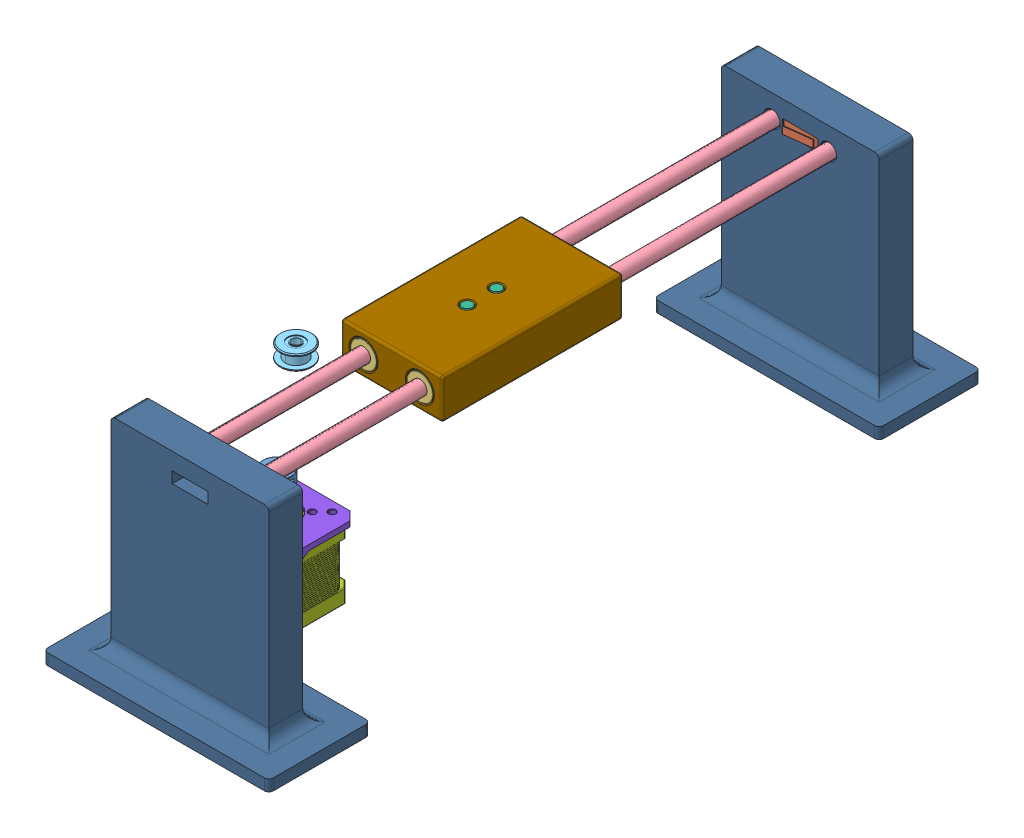
SolidWorks assembly TrackerPlatform, configuration Default. Lengths in mm.
Overall size (127 141.21 400.8).
21 component instances, 11 part files, 37 mates.
Components (placement in the parent):
- Teeth GT2 Pulley^TrackerPlatform-1: Teeth GT2 Pulley^TrackerPlatform [Varsayılan] at (44.45 -33.8487 -29.98) x (-0.053462 0 -0.99857) z (0 -1 0) size (16 16 14) (virtual)
- SPDT Lever Switch^TrackerPlatform-1: SPDT Lever Switch^TrackerPlatform [Default] at (44.417 -15.925 -329.85) x (-1 0 0) z (0 0 -1) size (20 6.4 16.53) (virtual)
- SPDT Lever Switch^TrackerPlatform-2: SPDT Lever Switch^TrackerPlatform [Default] at (44.417 -15.925 5.25) size (20 6.4 16.53) (virtual)
- LMU8 Linear Bearing^TrackerPlatform-1: LMU8 Linear Bearing^TrackerPlatform [Default] at (60.325 -12.7 -196.1468) size (15 15 24) (virtual)
- LMU8 Linear Bearing^TrackerPlatform-2: LMU8 Linear Bearing^TrackerPlatform [Default] at (28.575 -12.7 -172.1468) x (0.923728 0.383049 0) z (0 0 -1) size (15 15 24) (virtual)
- LMU8 Linear Bearing^TrackerPlatform-3: LMU8 Linear Bearing^TrackerPlatform [Default] at (60.325 -12.7 -118.5468) size (15 15 24) (virtual)
- LMU8 Linear Bearing^TrackerPlatform-4: LMU8 Linear Bearing^TrackerPlatform [Default] at (28.575 -12.7 -118.5468) size (15 15 24) (virtual)
- 350mm Linear Rail^TrackerPlatform-1: 350mm Linear Rail^TrackerPlatform [Default] at (60.325 -12.7 -337.3) x (0.609712 0.792623 0) z (0 0 1) size (8 8 350) (virtual)
- 350mm Linear Rail^TrackerPlatform-2: 350mm Linear Rail^TrackerPlatform [Default] at (28.575 -12.7 -337.3) x (0 -1 0) z (0 0 1) size (8 8 350) (virtual)
- Idler GT2-6 5mm.step^TrackerPlatform-2: Idler GT2-6 5mm.step^TrackerPlatform [Default] at (36.4446 16.3069 -48.6935) size (17.85 8.51 17.85) (virtual)
- 1-4x1.75 Dowel Pin^TrackerPlatform-1: 1-4x1.75 Dowel Pin^TrackerPlatform [Default] at (44.45 -46.0375 -153.6018) size (6.35 44.45 6.35) (virtual)
- 1-4x1.75 Dowel Pin^TrackerPlatform-2: 1-4x1.75 Dowel Pin^TrackerPlatform [Default] at (44.45 -46.0375 -137.0918) size (6.35 44.45 6.35) (virtual)
- Motor N17^TrackerPlatform-1: Motor N17^TrackerPlatform [Predeterminado] at (44.45 -92.0487 -29.98) x (0 0 -1) z (1 0 0) size (42.3 64.2 42.3) (virtual)
- NEMA 17 Motor Mount.step^TrackerPlatform-1: NEMA 17 Motor Mount.step^TrackerPlatform [Default] at (44.45 -2.0287 -3) x (0 -1 0) z (1 0 0) size (52.98 50.98 50) (virtual)
- Carriage^TrackerPlatform-1: Carriage^TrackerPlatform [Default] at (44.45 -23.8125 -145.3468) x (0 0 1) z (-1 0 0) size (101.6 22.23 57.15) (virtual)
- End Fixture^TrackerPlatform-1: End Fixture^TrackerPlatform [Default] at (44.45 -57.15 0) x (0 -1 0) z (-1 0 0) size (120.65 57.15 127) (virtual)
- End Fixture^TrackerPlatform-2: End Fixture^TrackerPlatform [Default] at (44.45 -57.15 -324.6) x (0 -1 0) z (1 0 0) size (120.65 57.15 127) (virtual)
- 2.5mmx5mm Standoff^TrackerPlatform-1: 2.5mmx5mm Standoff^TrackerPlatform [Default] at (-2.0742 -59.3398 -100.3321) size (4.9 4.9 5) (hidden, virtual)
- 2.5mmx5mm Standoff^TrackerPlatform-2: 2.5mmx5mm Standoff^TrackerPlatform [Default] at (-1.6992 -73.9326 -103.4686) size (4.9 4.9 5) (hidden, virtual)
- 2.5mmx5mm Standoff^TrackerPlatform-3: 2.5mmx5mm Standoff^TrackerPlatform [Default] at (-3.151 -75.2751 -95.8726) size (4.9 4.9 5) (hidden, virtual)
- 2.5mmx5mm Standoff^TrackerPlatform-4: 2.5mmx5mm Standoff^TrackerPlatform [Default] at (-9.8476 -68.7081 -99.2982) size (4.9 4.9 5) (hidden, virtual)
Mates (geometry in assembly coordinates):
- Concentric1: concentric: cylinder of LMU8 Linear Bearing^TrackerPlatform-3 through (60.325 -12.7 -94.5468) axis (0 0 -1) radius 7.5; cylinder of Carriage^TrackerPlatform-1 through (60.325 -12.7 -118.5468) axis (0 0 1) radius 7.55
- Coincident1: coincident: plane of LMU8 Linear Bearing^TrackerPlatform-3 through (60.325 -12.7 -94.5468) normal (0 0 1); plane of Carriage^TrackerPlatform-1 through (15.875 -1.5875 -94.5468) normal (0 0 1)
- Coincident2: coincident: plane of LMU8 Linear Bearing^TrackerPlatform-4 through (28.575 -12.7 -118.5468) normal (0 0 -1); plane of Carriage^TrackerPlatform-1 through (28.575 -12.7 -118.5468) normal (0 0 1)
- Concentric2: concentric: cylinder of LMU8 Linear Bearing^TrackerPlatform-4 through (28.575 -12.7 -94.5468) axis (0 0 -1) radius 7.5; cylinder of Carriage^TrackerPlatform-1 through (28.575 -12.7 -118.5468) axis (0 0 1) radius 7.55
- Coincident3: coincident: plane of LMU8 Linear Bearing^TrackerPlatform-1 through (60.325 -12.7 -172.1468) normal (0 0 1); plane of Carriage^TrackerPlatform-1 through (60.325 -12.7 -172.1468) normal (0 0 -1)
- Concentric3: concentric: cylinder of LMU8 Linear Bearing^TrackerPlatform-1 through (60.325 -12.7 -172.1468) axis (0 0 -1) radius 7.5; cylinder of Carriage^TrackerPlatform-1 through (60.325 -12.7 -172.1468) axis (0 0 -1) radius 7.55
- Coincident4: coincident: plane of LMU8 Linear Bearing^TrackerPlatform-2 through (28.575 -12.7 -172.1468) normal (0 0 1); plane of Carriage^TrackerPlatform-1 through (28.575 -12.7 -172.1468) normal (0 0 -1)
- Concentric4: concentric: cylinder of LMU8 Linear Bearing^TrackerPlatform-2 through (28.575 -12.7 -196.1468) axis (0 0 1) radius 7.5; cylinder of Carriage^TrackerPlatform-1 through (28.575 -12.7 -172.1468) axis (0 0 -1) radius 7.55
- Concentric5: concentric: cylinder of LMU8 Linear Bearing^TrackerPlatform-1 through (60.325 -12.7 -172.1468) axis (0 0 -1) radius 4; cylinder of 350mm Linear Rail^TrackerPlatform-1 through (60.325 -12.7 12.7) axis (0 0 -1) radius 4
- Concentric6: concentric: cylinder of LMU8 Linear Bearing^TrackerPlatform-2 through (28.575 -12.7 -196.1468) axis (0 0 1) radius 4; cylinder of 350mm Linear Rail^TrackerPlatform-2 through (28.575 -12.7 12.7) axis (0 0 -1) radius 4
- Coincident5: coincident: plane of 350mm Linear Rail^TrackerPlatform-1 through (60.325 -12.7 -337.3) normal (0 0 -1); plane of 350mm Linear Rail^TrackerPlatform-2 through (28.575 -12.7 -337.3) normal (0 0 -1)
- Concentric7: concentric: cylinder of 1-4x1.75 Dowel Pin^TrackerPlatform-1 through (44.45 -1.5875 -153.6018) axis (0 -1 0) radius 3.175; cylinder of Carriage^TrackerPlatform-1 through (44.45 -23.8125 -153.6018) axis (0 1 0) radius 3.175
- Coincident7: coincident: plane of 1-4x1.75 Dowel Pin^TrackerPlatform-1 through (44.45 -1.5875 -153.6018) normal (0 1 0); plane of Carriage^TrackerPlatform-1 through (44.45 -1.5875 -145.3468) normal (0 1 0)
- Concentric9: concentric: cylinder of 1-4x1.75 Dowel Pin^TrackerPlatform-2 through (44.45 -1.5875 -137.0918) axis (0 -1 0) radius 3.175; cylinder of Carriage^TrackerPlatform-1 through (44.45 -23.8125 -137.0918) axis (0 1 0) radius 3.175
- Coincident8: coincident: plane of 1-4x1.75 Dowel Pin^TrackerPlatform-2 through (44.45 -1.5875 -137.0918) normal (0 1 0); plane of Carriage^TrackerPlatform-1 through (44.45 -1.5875 -145.3468) normal (0 1 0)
- Coincident12: coincident: plane of End Fixture^TrackerPlatform-1 through (44.45 -57.15 0) normal (0 0 -1); plane of assembly through (0 0 0) normal (0 0 1)
- Coincident13: coincident: plane of End Fixture^TrackerPlatform-1 through (0 0 19.05) normal (0 1 0); plane of assembly through (0 0 0) normal (0 1 0)
- Coincident14: coincident: plane of End Fixture^TrackerPlatform-1 through (0 0 19.05) normal (-1 0 0); plane of assembly through (0 0 0) normal (1 0 0)
- Concentric10: concentric: cylinder of 350mm Linear Rail^TrackerPlatform-2 through (28.575 -12.7 12.7) axis (0 0 -1) radius 4; cylinder of End Fixture^TrackerPlatform-1 through (28.575 -12.7 12.7) axis (0 0 -1) radius 4
- Coincident15: coincident: plane of 350mm Linear Rail^TrackerPlatform-1 through (60.325 -12.7 12.7) normal (0 0 1); plane of End Fixture^TrackerPlatform-1 through (60.325 -12.7 12.7) normal (0 0 -1)
- Concentric11: concentric: cylinder of 350mm Linear Rail^TrackerPlatform-1 through (60.325 -12.7 12.7) axis (0 0 -1) radius 4; cylinder of End Fixture^TrackerPlatform-1 through (60.325 -12.7 12.7) axis (0 0 -1) radius 4
- Coincident16: coincident: plane of Motor N17^TrackerPlatform-1 through (44.45 -52.0487 -29.98) normal (0 1 0); plane of NEMA 17 Motor Mount.step^TrackerPlatform-1 through (44.45 -52.0487 -50.98) normal (0 -1 0)
- Concentric12: concentric: cylinder of Motor N17^TrackerPlatform-1 through (59.95 -59.0487 -45.48) axis (0 1 0) radius 1.25; cylinder of NEMA 17 Motor Mount.step^TrackerPlatform-1 through (59.95 -49.0487 -45.48) axis (0 -1 0) radius 1.75
- Concentric13: concentric: cylinder of Motor N17^TrackerPlatform-1 through (28.95 -59.0487 -14.48) axis (0 1 0) radius 1.25; cylinder of NEMA 17 Motor Mount.step^TrackerPlatform-1 through (28.95 -49.0487 -14.48) axis (0 -1 0) radius 1.75
- Concentric14: concentric: cylinder of Teeth GT2 Pulley^TrackerPlatform-1 through (44.45 -40.8487 -29.98) axis (0 1 0) radius 2.5; cylinder of Motor N17^TrackerPlatform-1 through (44.45 -27.8487 -29.98) axis (0 -1 0) radius 2.5
- Coincident17: coincident: plane of Teeth GT2 Pulley^TrackerPlatform-1 through (44.45 -27.8487 -29.98) normal (0 1 0); plane of Motor N17^TrackerPlatform-1 through (44.45 -27.8487 -29.98) normal (0 1 0)
- Coincident18: coincident: plane of NEMA 17 Motor Mount.step^TrackerPlatform-1 through (44.45 -2.0287 0) normal (0 0 1); plane of End Fixture^TrackerPlatform-1 through (44.45 -57.15 0) normal (0 0 -1)
- Coincident19: coincident: plane of Motor N17^TrackerPlatform-1 through (44.45 -92.0487 -29.98) normal (1 0 0); plane of End Fixture^TrackerPlatform-1 through (44.45 -57.15 0) normal (-1 0 0)
- Coincident20: coincident: plane of SPDT Lever Switch^TrackerPlatform-2 through (53.417 -9.525 1) normal (0 1 0); plane of End Fixture^TrackerPlatform-1 through (54.483 -9.525 38.1) normal (0 -1 0)
- Coincident21: coincident: plane of SPDT Lever Switch^TrackerPlatform-2 through (34.417 -9.525 1) normal (-1 0 0); plane of End Fixture^TrackerPlatform-1 through (34.417 -15.875 38.1) normal (1 0 0)
- Coincident22: coincident: plane of SPDT Lever Switch^TrackerPlatform-2 through (35.417 -9.525 0) normal (0 0 -1); plane of End Fixture^TrackerPlatform-1 through (44.45 -57.15 0) normal (0 0 -1)
- Concentric15: concentric: cylinder of End Fixture^TrackerPlatform-2 through (28.575 -12.7 -337.3) axis (0 0 1) radius 4; cylinder of 350mm Linear Rail^TrackerPlatform-2 through (28.575 -12.7 12.7) axis (0 0 -1) radius 4
- Concentric16: concentric: cylinder of 350mm Linear Rail^TrackerPlatform-1 through (60.325 -12.7 12.7) axis (0 0 -1) radius 4; cylinder of End Fixture^TrackerPlatform-2 through (60.325 -12.7 -337.3) axis (0 0 1) radius 4
- Coincident23: coincident: plane of 350mm Linear Rail^TrackerPlatform-1 through (60.325 -12.7 -337.3) normal (0 0 -1); plane of End Fixture^TrackerPlatform-2 through (60.325 -12.7 -337.3) normal (0 0 1)
- Coincident24: coincident: plane of SPDT Lever Switch^TrackerPlatform-1 through (35.417 -9.525 -325.6) normal (0 1 0); plane of End Fixture^TrackerPlatform-2 through (34.417 -9.525 -362.7) normal (0 -1 0)
- Coincident25: coincident: plane of SPDT Lever Switch^TrackerPlatform-1 through (34.417 -9.525 -325.6) normal (-1 0 0); plane of End Fixture^TrackerPlatform-2 through (34.417 -15.875 -362.7) normal (1 0 0)
- Coincident26: coincident: plane of SPDT Lever Switch^TrackerPlatform-1 through (53.417 -9.525 -324.6) normal (0 0 1); plane of End Fixture^TrackerPlatform-2 through (44.45 -57.15 -324.6) normal (0 0 1)
